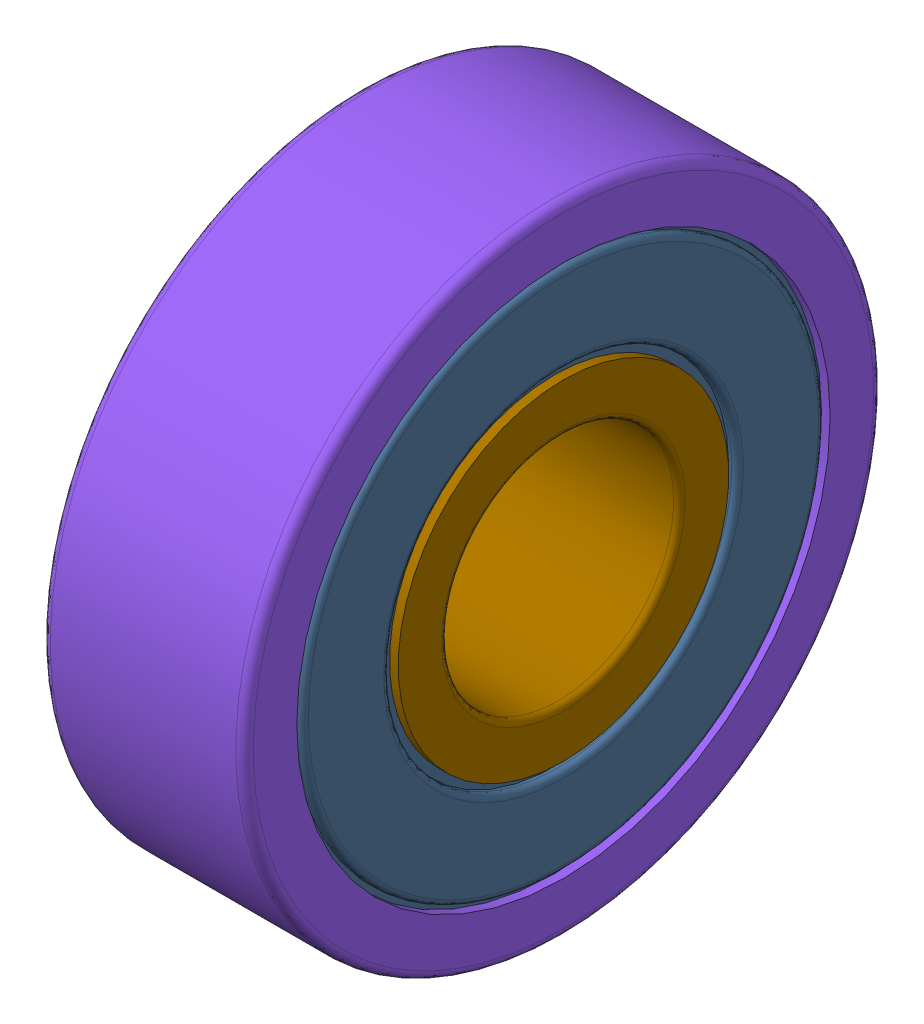
SolidWorks assembly Ball Bearing 8 x 22 x 7mm, configuration Default. Lengths in mm.
Overall size (7 22 22).
21 component instances, 20 part files, 0 mates.
Components (placement in the parent):
- 608-2RS Skate Board Ball Bearing.step-1: 608-2RS Skate Board Ball Bearing.step [Default] at origin size (7 22 22)
  - Ball 001.step-1: Ball 001.step [Default] at (0 0 7.5) size (4 4 4)
  - Ball 002.step-1: Ball 002.step [Default] at (0 5.8637 4.6762) x (1 0 0) z (0 0.781831 0.62349) size (4 4 4)
  - Ball 003.step-1: Ball 003.step [Default] at (0 7.312 -1.6689) x (1 0 0) z (0 0.974928 -0.222521) size (4 4 4)
  - Ball 004.step-1: Ball 004.step [Default] at (0 3.2541 -6.7573) x (1 0 0) z (0 0.433884 -0.900969) size (4 4 4)
  - Ball 005.step-1: Ball 005.step [Default] at (0 -3.2541 -6.7573) x (1 0 0) z (0 -0.433884 -0.900969) size (4 4 4)
  - Ball 006.step-1: Ball 006.step [Default] at (0 -7.312 -1.6689) x (1 0 0) z (0 -0.974928 -0.222521) size (4 4 4)
  - Ball 007.step-1: Ball 007.step [Default] at (0 -5.8637 4.6762) x (1 0 0) z (0 -0.781831 0.62349) size (4 4 4)
  - Outer Ring001.step-1: Outer Ring001.step [Default] at origin size (7 22 22)
  - Inner Ring001.step-1: Inner Ring001.step [Default] at origin size (7 12 12)
  - Seal 001.step-1: Seal 001.step [Default] at origin size (0.6 19 19)
  - Seal 002.step-1: Seal 002.step [Default] x (-1 0 0) z (0 0 -1) size (0.6 19 19)
  - Cage 001.step-1: Cage 001.step [Default] at origin size (2.31 17.85 17.41)
  - Cage clone 002.step-1: Cage clone 002.step [Default] x (-1 0 0) z (0 0 1) size (2.31 17.85 17.41)
  - Rivet 002.step-1: Rivet 002.step [Default] at (0 3.2541 6.7573) x (1 0 0) z (0 0.433884 0.900969) size (0.8 0.8 0.8)
  - Rivet 001.step-1: Rivet 001.step [Default] at (0 -3.2541 6.7573) x (1 0 0) z (0 -0.433884 0.900969) size (0.8 0.8 0.8)
  - Rivet 007.step-1: Rivet 007.step [Default] at (0 5.8637 -4.6762) x (1 0 0) z (0 0.781831 -0.62349) size (0.8 0.8 0.8)
  - Rivet 006.step-1: Rivet 006.step [Default] at (0 7.312 1.6689) x (1 0 0) z (0 0.974928 0.222521) size (0.8 0.8 0.8)
  - Rivet 005.step-1: Rivet 005.step [Default] at (0 -7.312 1.6689) x (1 0 0) z (0 -0.974928 0.222521) size (0.8 0.8 0.8)
  - Rivet 004.step-1: Rivet 004.step [Default] at (0 -5.8637 -4.6762) x (1 0 0) z (0 -0.781831 -0.62349) size (0.8 0.8 0.8)
  - Rivet 003.step-1: Rivet 003.step [Default] at (0 0 -7.5) x (1 0 0) z (0 0 -1) size (0.8 0.8 0.8)
